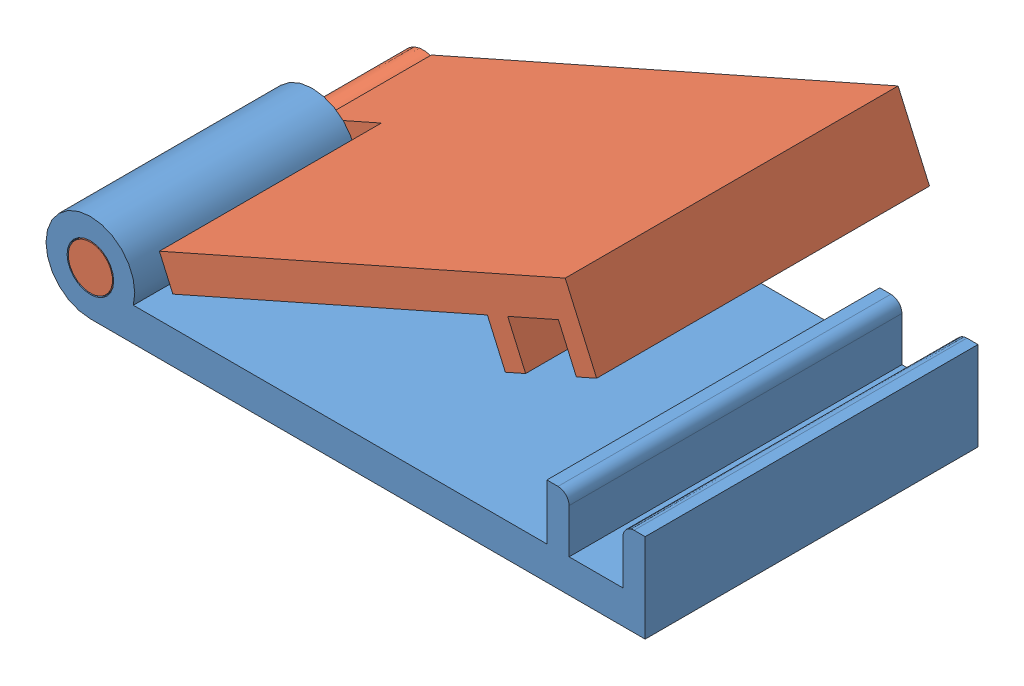
SolidWorks assembly Assem1, configuration Default. Lengths in mm.
Overall size (54 26.88 30).
2 component instances, 2 part files, 2 mates.
Components (placement in the parent):
- camera_holder_lower-1: camera_holder_lower [Default] at (10.0403 -6.141 -16.7691) size (54 8 30)
- camera_holder_upper-1: camera_holder_upper [Default] at (10.1558 7.4741 -16.7691) x (0.91445 0.404698 0) z (0 0 1) size (49.47 7.5 30)
Mates (geometry in assembly coordinates):
- Coincident1: coincident: plane of camera_holder_lower-1 through (10.0403 -6.141 13.2309) normal (0 0 1); plane of camera_holder_upper-1 through (10.1558 7.4741 13.2309) normal (0 0 1)
- Concentric1: concentric: circle of camera_holder_lower-1; circle of camera_holder_upper-1
